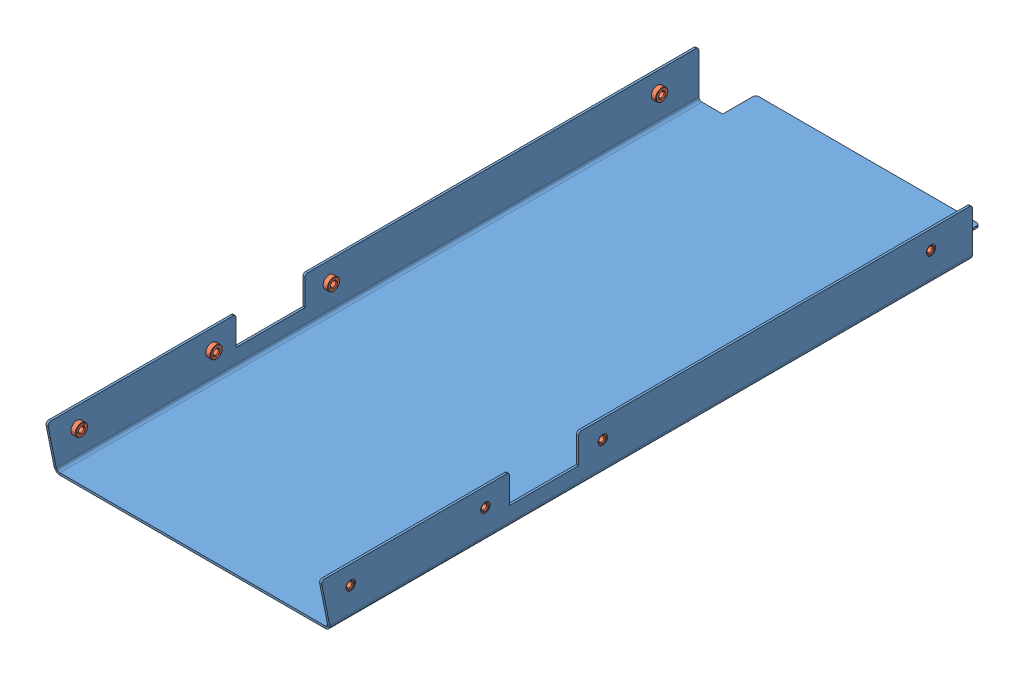
SolidWorks assembly GE-22333, configuration Default. Lengths in mm.
Overall size (253.49 44.45 628.55).
9 component instances, 2 part files, 24 mates.
Components (placement in the parent):
- GE-22333-01-1: GE-22333-01 [Default] at origin size (253.49 44.45 628.55)
- pem_clinchnut_.25_20_.054-1: pem_clinchnut_.25_20_.054 [Default] at (0.6223 25.4 -38.1) size (5.69 11.18 11.18)
- pem_clinchnut_.25_20_.054-6: pem_clinchnut_.25_20_.054 [Default] at (0.6223 25.4 -571.5) x (1 0 0) z (0 -0.371154 0.928571) size (5.69 11.18 11.18)
- pem_clinchnut_.25_20_.054-8: pem_clinchnut_.25_20_.054 [Default] at (252.8697 25.4 -571.5) x (-1 0 0) z (0 -0.421154 -0.906989) size (5.69 11.18 11.18)
- pem_clinchnut_.25_20_.054-14: pem_clinchnut_.25_20_.054 [Default] at (252.8697 25.4 -38.1) x (-1 0 0) z (0 -0.305088 -0.952324) size (5.69 11.18 11.18)
- pem_clinchnut_.25_20_.054-16: pem_clinchnut_.25_20_.054 [Default] at (252.8697 25.4 -161.925) x (-1 0 0) z (0 -0.158553 -0.987351) size (5.69 11.18 11.18)
- pem_clinchnut_.25_20_.054-18: pem_clinchnut_.25_20_.054 [Default] at (252.8697 25.4 -269.875) x (-1 0 0) z (0 -0.282984 -0.959125) size (5.69 11.18 11.18)
- pem_clinchnut_.25_20_.054-20: pem_clinchnut_.25_20_.054 [Default] at (0.6223 25.4 -269.875) x (1 0 0) z (0 -0.371154 0.928571) size (5.69 11.18 11.18)
- pem_clinchnut_.25_20_.054-22: pem_clinchnut_.25_20_.054 [Default] at (0.6223 25.4 -161.925) x (1 0 0) z (0 -0.421154 0.906989) size (5.69 11.18 11.18)
Mates (geometry in assembly coordinates):
- Concentric1: concentric aligned: cylinder of GE-22333-01-1 through (0 25.4 -38.1) axis (-1 0 0) radius 4.3688; cylinder of pem_clinchnut_.25_20_.054-1 through (1.651 25.4 -38.1) axis (-1 0 0) radius 4.9721
- Coincident1: coincident anti-aligned: plane of GE-22333-01-1 through (1.9939 0 0) normal (1 0 0); plane of pem_clinchnut_.25_20_.054-1 through (1.9939 25.4 -35.306) normal (-1 0 0)
- Concentric2: concentric aligned: cylinder of lowChuteBackRamp_hybrid_mockV2-1 through (0 25.4 -139.7) axis (-1 0 0) radius 4.3688; cylinder of pem_clinchnut_.25_20_.054-2 through (2.0193 25.4 -139.7) axis (-1 0 0) radius 4.9721
- Coincident2: coincident anti-aligned: plane of GE-22333-01-1 through (1.9939 0 0) normal (1 0 0); plane of pem_clinchnut_.25_20_.054-2 through (2.3622 24.957 -136.9413) normal (-1 0 0)
- Concentric3: concentric aligned: cylinder of lowChuteBackRamp_hybrid_mockV2-1 through (0 25.4 -469.9) axis (-1 0 0) radius 3.7592; cylinder of pem_clinchnut_.25_20_.054-4 through (1.5545 25.4 -469.9) axis (-1 0 0) radius 4.9721
- Coincident3: coincident anti-aligned: plane of GE-22333-01-1 through (1.9939 0 0) normal (1 0 0); plane of pem_clinchnut_.25_20_.054-4 through (1.8974 24.6093 -467.2202) normal (-1 0 0)
- Concentric4: concentric aligned: cylinder of GE-22333-01-1 through (0 25.4 -571.5) axis (-1 0 0) radius 4.3688; cylinder of pem_clinchnut_.25_20_.054-6 through (1.651 25.4 -571.5) axis (-1 0 0) radius 4.9721
- Coincident4: coincident anti-aligned: plane of GE-22333-01-1 through (1.9939 0 0) normal (1 0 0); plane of pem_clinchnut_.25_20_.054-6 through (1.9939 24.363 -568.9056) normal (-1 0 0)
- Concentric5: concentric anti-aligned: cylinder of GE-22333-01-1 through (0 25.4 -571.5) axis (-1 0 0) radius 4.3688; cylinder of pem_clinchnut_.25_20_.054-8 through (251.841 25.4 -571.5) axis (1 0 0) radius 4.9721
- Coincident5: coincident anti-aligned: plane of GE-22333-01-1 through (251.4981 0 0) normal (-1 0 0); plane of pem_clinchnut_.25_20_.054-8 through (251.4981 24.2233 -574.0341) normal (1 0 0)
- Concentric6: concentric anti-aligned: cylinder of lowChuteBackRamp_hybrid_mockV2-1 through (0 25.4 -469.9) axis (-1 0 0) radius 3.7592; cylinder of pem_clinchnut_.25_20_.054-10 through (251.9375 25.4 -469.9) axis (1 0 0) radius 4.9721
- Coincident6: coincident anti-aligned: plane of GE-22333-01-1 through (251.4981 0 0) normal (-1 0 0); plane of pem_clinchnut_.25_20_.054-10 through (251.5946 24.1987 -472.4226) normal (1 0 0)
- Concentric7: concentric anti-aligned: cylinder of lowChuteBackRamp_hybrid_mockV2-1 through (0 25.4 -139.7) axis (-1 0 0) radius 4.3688; cylinder of pem_clinchnut_.25_20_.054-12 through (245.6307 25.4 -139.7) axis (1 0 0) radius 4.9721
- Coincident7: coincident anti-aligned: plane of GE-22333-01-1 through (251.4981 0 0) normal (-1 0 0); plane of pem_clinchnut_.25_20_.054-12 through (245.2878 24.3025 -142.2694) normal (1 0 0)
- Concentric8: concentric anti-aligned: cylinder of GE-22333-01-1 through (0 25.4 -38.1) axis (-1 0 0) radius 4.3688; cylinder of pem_clinchnut_.25_20_.054-14 through (251.841 25.4 -38.1) axis (1 0 0) radius 4.9721
- Coincident8: coincident anti-aligned: plane of GE-22333-01-1 through (251.4981 0 0) normal (-1 0 0); plane of pem_clinchnut_.25_20_.054-14 through (251.4981 24.5476 -40.7608) normal (1 0 0)
- Concentric9: concentric anti-aligned: cylinder of GE-22333-01-1 through (0 25.4 -161.925) axis (-1 0 0) radius 4.3688; cylinder of pem_clinchnut_.25_20_.054-16 through (251.841 25.4 -161.925) axis (1 0 0) radius 4.9721
- Coincident9: coincident anti-aligned: plane of GE-22333-01-1 through (251.4981 0 0) normal (-1 0 0); plane of pem_clinchnut_.25_20_.054-16 through (251.4981 24.957 -164.6837) normal (1 0 0)
- Concentric10: concentric anti-aligned: cylinder of GE-22333-01-1 through (0 25.4 -269.875) axis (-1 0 0) radius 4.3688; cylinder of pem_clinchnut_.25_20_.054-18 through (251.841 25.4 -269.875) axis (1 0 0) radius 4.9721
- Coincident10: coincident anti-aligned: plane of GE-22333-01-1 through (251.4981 0 0) normal (-1 0 0); plane of pem_clinchnut_.25_20_.054-18 through (251.4981 24.6093 -272.5548) normal (1 0 0)
- Concentric11: concentric aligned: cylinder of GE-22333-01-1 through (0 25.4 -269.875) axis (-1 0 0) radius 4.3688; cylinder of pem_clinchnut_.25_20_.054-20 through (1.651 25.4 -269.875) axis (-1 0 0) radius 4.9721
- Coincident11: coincident anti-aligned: plane of GE-22333-01-1 through (1.9939 0 0) normal (1 0 0); plane of pem_clinchnut_.25_20_.054-20 through (1.9939 24.363 -267.2806) normal (-1 0 0)
- Concentric12: concentric aligned: cylinder of GE-22333-01-1 through (0 25.4 -161.925) axis (-1 0 0) radius 4.3688; cylinder of pem_clinchnut_.25_20_.054-22 through (1.651 25.4 -161.925) axis (-1 0 0) radius 4.9721
- Coincident12: coincident anti-aligned: plane of GE-22333-01-1 through (1.9939 0 0) normal (1 0 0); plane of pem_clinchnut_.25_20_.054-22 through (1.9939 24.2233 -159.3909) normal (-1 0 0)
